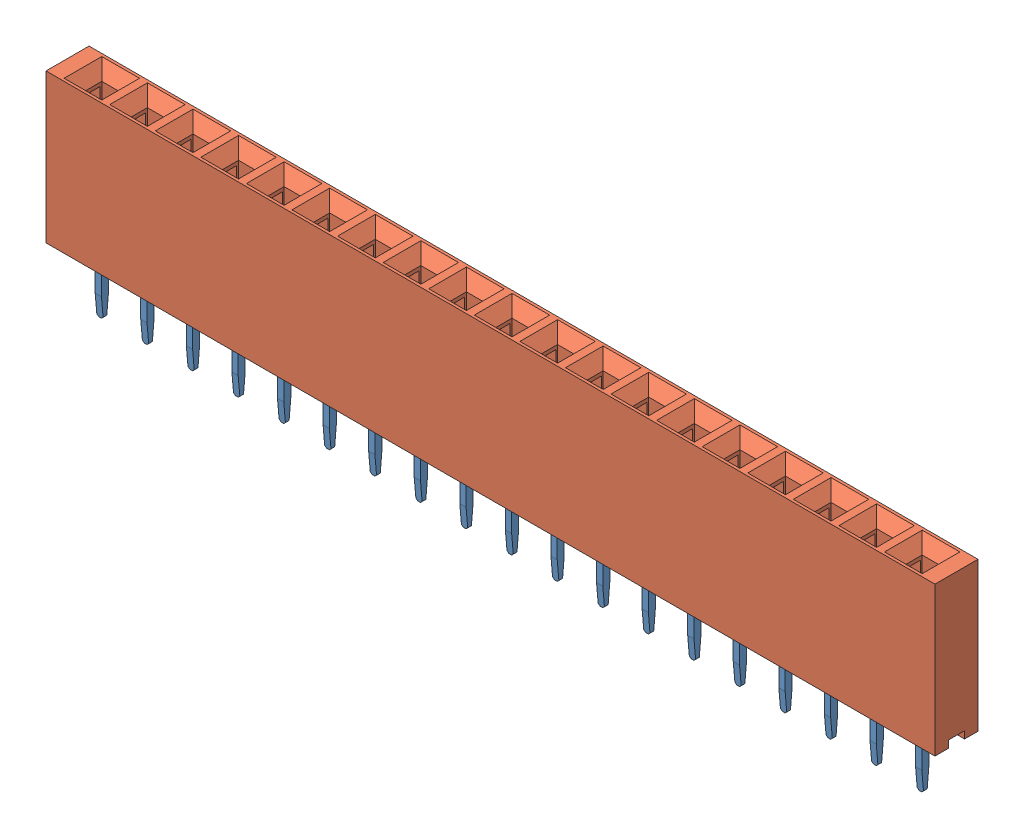
SolidWorks assembly 2_54_x_19_pitch_connector_, configuration Default. Lengths in mm.
Overall size (49.54 11.5 2.4).
2 component instances, 2 part files, 8 mates.
Components (placement in the parent):
- Pitch_x_19-1: Pitch_x_19 [Default] at origin size (47.67 8.86 0.39)
- Plastic_x_19-1: Plastic_x_19 [Default] x (1 0 0) z (0 1 0) size (49.54 2.4 8.3)
Mates (geometry in assembly coordinates):
- На месте1: in place: plane of Pitch_x_19-1 through (0 0 0) normal (0 0 1); moOrthogonalPlaneRef_w of Pitch_x_19-1 through (0 0 0) normal (0 1 0); plane of Pitch_x_19-1 through (0 0 0) normal (1 0 0); unknown of Pitch_x_19-1
- Совпадение1: coincident aligned: 
- Совпадение2: coincident aligned: plane of Деталь8^Сборка2-1 through (0 0 0) normal (0 1 0)
- Совпадение3: coincident anti-aligned: plane of Деталь8^Сборка2-1 through (0 0 0) normal (1 0 0)
- На месте2: in place: plane of Plastic_x_19-1 through (0 0 0) normal (0 1 0); plane of Plastic_x_19-1 through (0 0 0) normal (0 0 -1); plane of Plastic_x_19-1 through (0 0 0) normal (1 0 0); unknown of Plastic_x_19-1
- Совпадение4: coincident aligned: 
- Совпадение5: coincident aligned: plane of Plastic-1 through (0 0 0) normal (0 0 -1)
- Совпадение6: coincident anti-aligned: plane of Plastic-1 through (0 0 0) normal (1 0 0)
